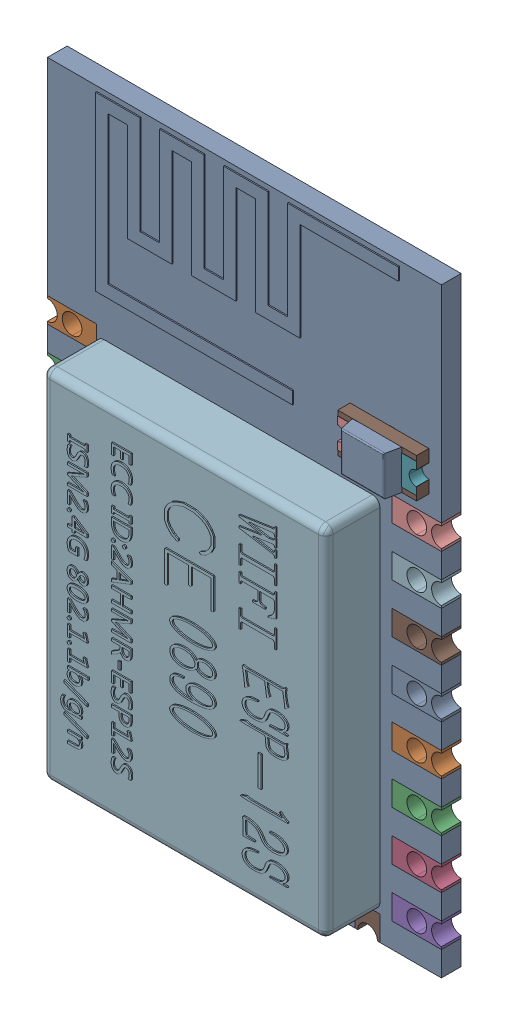
SolidWorks assembly P3, configuration ﾃﾞﾌｫﾙﾄ. Lengths in mm.
Overall size (16 24.38 3.05).
27 component instances, 6 part files, 0 mates.
Components (placement in the parent):
- 0411-2-1: 0411-2 [ﾃﾞﾌｫﾙﾄ] at (11.34 12.4403 0) x (0 1 0) z (-1 0 0) size (24.38 3.05 16)
  - User_Library-ESP8266-12E_PCB1-1: User_Library-ESP8266-12E_PCB1 [ﾃﾞﾌｫﾙﾄ] x (-1 0 0) z (0 0 1) size (24.38 0.8 16)
  - User_Library-ESP8266-12E_Pin1-1: User_Library-ESP8266-12E_Pin1 [ﾃﾞﾌｫﾙﾄ] at (3.31 0 8) x (-1 0 0) z (0 -1 0) size (1 2 0.8)
  - User_Library-ESP8266-12E_Pin1-2: User_Library-ESP8266-12E_Pin1 [ﾃﾞﾌｫﾙﾄ] at (1.31 0 8) x (-1 0 0) z (0 -1 0) size (1 2 0.8)
  - User_Library-ESP8266-12E_Pin1-3: User_Library-ESP8266-12E_Pin1 [ﾃﾞﾌｫﾙﾄ] at (-0.69 0 8) x (-1 0 0) z (0 -1 0) size (1 2 0.8)
  - User_Library-ESP8266-12E_Pin1-4: User_Library-ESP8266-12E_Pin1 [ﾃﾞﾌｫﾙﾄ] at (-2.69 0 8) x (-1 0 0) z (0 -1 0) size (1 2 0.8)
  - User_Library-ESP8266-12E_Pin1-5: User_Library-ESP8266-12E_Pin1 [ﾃﾞﾌｫﾙﾄ] at (-4.69 0 8) x (-1 0 0) z (0 -1 0) size (1 2 0.8)
  - User_Library-ESP8266-12E_Pin1-6: User_Library-ESP8266-12E_Pin1 [ﾃﾞﾌｫﾙﾄ] at (-6.69 0 8) x (-1 0 0) z (0 -1 0) size (1 2 0.8)
  - User_Library-ESP8266-12E_Pin1-7: User_Library-ESP8266-12E_Pin1 [ﾃﾞﾌｫﾙﾄ] at (-8.69 0 8) x (-1 0 0) z (0 -1 0) size (1 2 0.8)
  - User_Library-ESP8266-12E_Pin1-8: User_Library-ESP8266-12E_Pin1 [ﾃﾞﾌｫﾙﾄ] at (-10.69 0 8) x (-1 0 0) z (0 -1 0) size (1 2 0.8)
  - User_Library-ESP8266-12E_Pin1-9: User_Library-ESP8266-12E_Pin1 [ﾃﾞﾌｫﾙﾄ] at (3.31 0 -8) x (1 0 0) z (0 -1 0) size (1 2 0.8)
  - User_Library-ESP8266-12E_Pin1-10: User_Library-ESP8266-12E_Pin1 [ﾃﾞﾌｫﾙﾄ] at (-0.69 0 -8) x (1 0 0) z (0 -1 0) size (1 2 0.8)
  - User_Library-ESP8266-12E_Pin1-11: User_Library-ESP8266-12E_Pin1 [ﾃﾞﾌｫﾙﾄ] at (1.31 0 -8) x (1 0 0) z (0 -1 0) size (1 2 0.8)
  - User_Library-ESP8266-12E_Pin1-12: User_Library-ESP8266-12E_Pin1 [ﾃﾞﾌｫﾙﾄ] at (-2.69 0 -8) x (1 0 0) z (0 -1 0) size (1 2 0.8)
  - User_Library-ESP8266-12E_Pin1-13: User_Library-ESP8266-12E_Pin1 [ﾃﾞﾌｫﾙﾄ] at (-4.69 0 -8) x (1 0 0) z (0 -1 0) size (1 2 0.8)
  - User_Library-ESP8266-12E_Pin1-14: User_Library-ESP8266-12E_Pin1 [ﾃﾞﾌｫﾙﾄ] at (-6.69 0 -8) x (1 0 0) z (0 -1 0) size (1 2 0.8)
  - User_Library-ESP8266-12E_Pin1-15: User_Library-ESP8266-12E_Pin1 [ﾃﾞﾌｫﾙﾄ] at (-8.69 0 -8) x (1 0 0) z (0 -1 0) size (1 2 0.8)
  - User_Library-ESP8266-12E_Pin1-16: User_Library-ESP8266-12E_Pin1 [ﾃﾞﾌｫﾙﾄ] at (-10.69 0 -8) x (1 0 0) z (0 -1 0) size (1 2 0.8)
  - User_Library-ESP8266-12E_Pin2-1: User_Library-ESP8266-12E_Pin2 [ﾃﾞﾌｫﾙﾄ] at (-12.19 0 5) x (0 0 1) z (0 1 0) size (1 1 0.8)
  - User_Library-ESP8266-12E_Pin2-2: User_Library-ESP8266-12E_Pin2 [ﾃﾞﾌｫﾙﾄ] at (-12.19 0 3) x (0 0 -1) z (0 -1 0) size (1 1 0.8)
  - User_Library-ESP8266-12E_Pin2-3: User_Library-ESP8266-12E_Pin2 [ﾃﾞﾌｫﾙﾄ] at (-12.19 0 1) x (0 0 1) z (0 1 0) size (1 1 0.8)
  - User_Library-ESP8266-12E_Pin2-4: User_Library-ESP8266-12E_Pin2 [ﾃﾞﾌｫﾙﾄ] at (-12.19 0 -1) x (0 0 1) z (0 1 0) size (1 1 0.8)
  - User_Library-ESP8266-12E_Pin2-5: User_Library-ESP8266-12E_Pin2 [ﾃﾞﾌｫﾙﾄ] at (-12.19 0 -3) x (0 0 1) z (0 1 0) size (1 1 0.8)
  - User_Library-ESP8266-12E_Pin2-6: User_Library-ESP8266-12E_Pin2 [ﾃﾞﾌｫﾙﾄ] at (-12.19 0 -5) x (0 0 1) z (0 1 0) size (1 1 0.8)
  - User_Library-ESP8266-12E_Lid-1: User_Library-ESP8266-12E_Lid [ﾃﾞﾌｫﾙﾄ] at (-3.84 -1.5 0.25) x (0 0 -1) z (0 -1 0) size (11.5 14.5 2.25)
  - User_Library-ESP8266-12E_Antenne-1: User_Library-ESP8266-12E_Antenne [ﾃﾞﾌｫﾙﾄ] at (4.99 -0.425 6) x (0 0 -1) z (0 -1 0) size (12.3 7 0.05)
  - User_Library-ESP8266-12E_Surface_Mount_Chip_LED_3.2x1.6mm-1: User_Library-ESP8266-12E_Surface_Mount_Chip_LED_3.2x1.6mm [ﾃﾞﾌｫﾙﾄ] at (6.19 -0.41 -7.5) x (0 0 1) z (0 -1 0) size (3.2 1.6 1.13)
